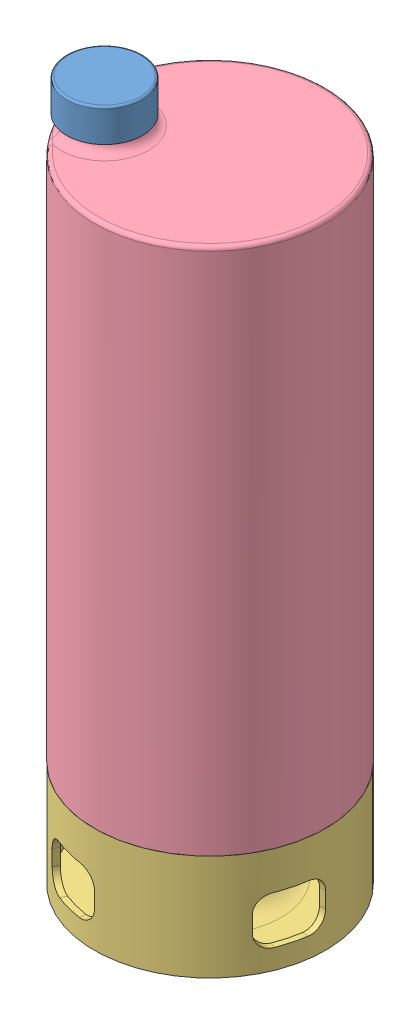
SolidWorks assembly Full Assembly, configuration Default. Lengths in mm.
Overall size (155.43 339.5 155.43).
5 component instances, 5 part files, 7 mates.
Components (placement in the parent):
- cap-1: cap [Default] at (-121.9169 254.8564 117.7654) x (-0.034156 0 0.999417) z (-0.999417 0 -0.034156) size (38 17.8 38)
- elevator-1: elevator [Default] at (-83.6174 38.1234 103.1314) x (0.735714 0 -0.677293) z (0.677293 0 0.735714) size (110 120 110)
- Shell Lower-1: Shell Lower [Default] at (-83.6174 34.8564 103.1314) size (116 103 116)
- Shell Upper-1: Shell Upper [Default] at (-83.6174 34.8564 103.1314) x (0.934133 0 -0.356926) z (0.356926 0 0.934133) size (117.98 286.45 116)
- Spring 2-1: Spring 2 [Default] at (-83.6174 -65.1436 103.1314) x (0.38907 0 0.921208) z (-0.921208 0 0.38907) size (32.11 103.35 31.68)
Mates (geometry in assembly coordinates):
- Concentric4: concentric: cylinder of Shell Lower-1 through (-83.6174 34.8564 103.1314) axis (0 -1 0) radius 16.5; line of Spring 2-1 through (-83.6174 -65.1436 103.1314) axis (0 1 0)
- Coincident4: coincident: plane of Shell Lower-1 through (-100.1174 -65.1436 103.1314) normal (0 1 0); plane of Spring 2-1 through (-83.6174 -65.1436 103.1314) normal (0 -1 0)
- Concentric5: concentric: cylinder of elevator-1 through (-83.6174 -49.4045 103.1314) axis (0 -1 0) radius 14; line of Spring 2-1 through (-83.6174 -65.1436 103.1314) axis (0 1 0)
- Concentric6: concentric: cylinder of Shell Lower-1 through (-83.6174 34.8564 103.1314) axis (0 -1 0) radius 58; cylinder of Shell Upper-1 through (-83.6174 34.8564 103.1314) axis (0 -1 0) radius 58
- Coincident6: coincident: circle of Shell Lower-1; circle of Shell Upper-1
- Concentric7: concentric: circle of cap-1; circle of Shell Upper-1
- Coincident8: coincident: plane of cap-1 through (-121.9169 269.8564 117.7654) normal (0 -1 0); plane of Shell Upper-1 through (-121.9169 269.8564 117.7654) normal (0 1 0)
